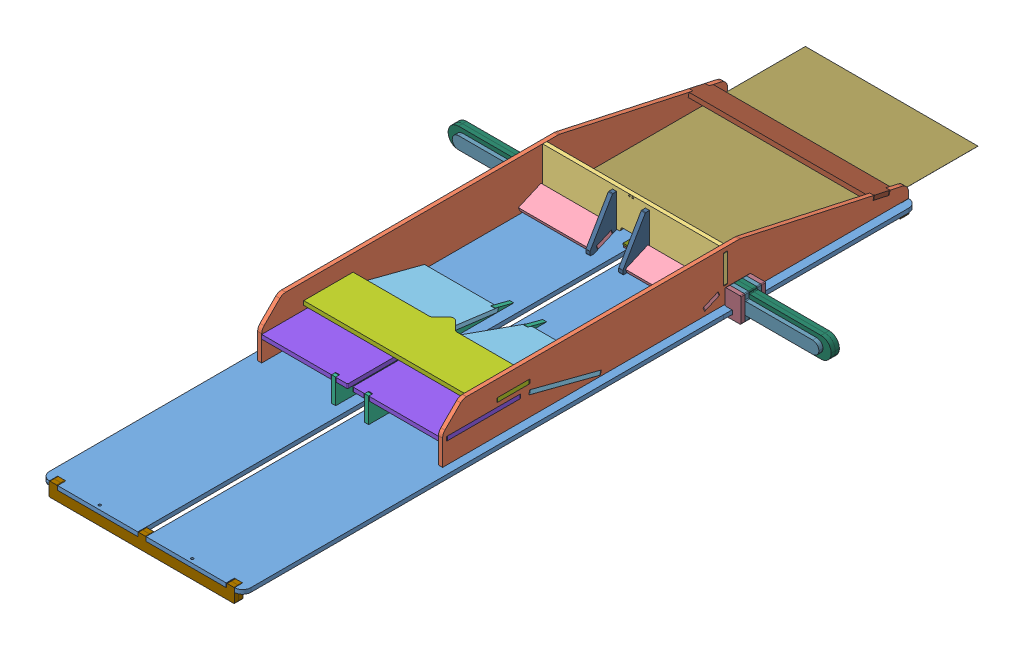
SolidWorks assembly assembly plane folder, configuration Default. Lengths in mm.
Overall size (466 77 820).
30 component instances, 16 part files, 6 mates.
Components (placement in the parent):
- frame-1: frame [Default] at (-2.7129 -3.6474 600) size (245.6 77 820)
  - backplate-1: backplate [Default] at (-118.702 1.298 900) size (245.6 5 820)
  - side-1: side [Default] at (-108.702 86.298 910) x (0 -1 0) z (1 0 0) size (64.9 566.78 5)
  - side-2: side [Default] at (111.298 86.298 910) x (0 -1 0) z (1 0 0) size (64.9 566.78 5)
  - frame-folder-1: frame-folder [Default] at (-103.702 21.248 530) size (225 45 5)
  - frame-folder2-1: frame-folder2 [Default] at (111.298 13.9006 564.4496) x (-1 0 0) z (0 -0.916515 -0.4) size (95 30 5)
  - frame-folder2-2: frame-folder2 [Default] at (-18.702 13.8606 564.5413) x (-1 0 0) z (0 -0.916515 -0.4) size (95 30 5)
  - frame-secondfold-1: frame-secondfold [Default] at (-103.702 31.4463 776.7345) x (1 0 0) z (0 0.967829 -0.251609) size (109.34 100 5)
  - frame-secondfold3-1: frame-secondfold3 [Default] at (-18.702 1.298 906.1881) x (0 0 -1) z (1 0 0) size (216.66 35.16 5)
  - frame-secondfold-3: frame-secondfold [Default] at (111.298 36.2855 775.3765) x (-1 0 0) z (0 -0.967829 0.251609) size (109.34 100 5)
  - frame-secondfold3-2: frame-secondfold3 [Default] at (21.298 1.298 906.0881) x (0 0 -1) z (1 0 0) size (216.66 35.16 5)
  - frame-secondfold1-1: frame-secondfold1 [Default] at (-103.702 41.4589 825.6357) x (1 0 0) z (0 1 0) size (225 72.93 5)
  - frame-secondfold4-1: frame-secondfold4 [Default] at (-103.702 31.4589 876.8329) x (1 0 0) z (0 1 0) size (109.5 100.05 5)
  - frame-secondfold4-2: frame-secondfold4 [Default] at (111.298 31.4589 776.6329) x (-1 0 0) z (0 1 0) size (109.5 100.05 5)
  - stopper-1: stopper [Default] at (-109.002 -10.702 1125) size (225.6 17 5)
  - stopper-2: stopper [Default] at (-109.002 -10.702 1120) size (225.6 17 5)
  - stopper-3: stopper [Default] at (-109.002 -10.702 315) size (225.6 17 5)
  - stopper-4: stopper [Default] at (-109.002 -10.702 310) size (225.6 17 5)
  - frame-folder4-1: frame-folder4 [Default] at (-18.702 61.198 535) x (0 -1 0) z (1 0 0) size (52 37.5 5)
  - frame-folder4-2: frame-folder4 [Default] at (21.298 61.198 535) x (0 -1 0) z (1 0 0) size (52 37.5 5)
  - frame-paperholder-1: frame-paperholder [Default] at (-108.702 25.1666 327.6234) x (1 0 0) z (0 -0.976744 0.214407) size (225 30 5)
- A4 paper-1: A4 paper [Default] at (-103.9148 7.9007 1115) x (1 0 0) z (0 1 0) size (210 297 0.1) (hidden)
- slider2-1: slider2 [Default] at (-49.729 -16.7544 842.5) size (466 32.7 30.31)
  - slider2-1-1: slider2-1 [Default] at (-81.7359 9.355 262.5) size (266 30 5)
  - slider2-2-1: slider2-2 [Default] at (-81.7359 9.355 267.5) size (446 30 5)
  - slider2-3-1: slider2-3 [Default] at (-81.7359 9.355 272.5) size (466 30 5)
  - slider2-3-2: slider2-3 [Default] at (-81.7359 9.355 277.5) size (466 30 5)
  - slider2-2-2: slider2-2 [Default] at (-81.7359 9.355 282.5) size (446 30 5)
  - slider2-1-2: slider2-1 [Default] at (-81.7359 9.355 287.5) size (266 30 5)
  - clip2-1: clip2 [Default] at (41.0141 21.655 292.5) x (1 0 0) z (0 1 0) size (20.89 30.31 20.4) (hidden)
Mates (geometry in assembly coordinates):
- Distance3: distance = 2.5 mm anti-aligned: plane of A4 paper-1 through (-103.9148 8.0007 1115) normal (-1 0 0); plane of frame-1/side-1 through (-106.4148 82.6507 1510) normal (1 0 0)
- Distance4: distance = 0.05 mm anti-aligned: plane of slider2-1/slider2-1-2 through (-121.4648 -2.3993 1135) normal (0 1 0); plane of frame-1/backplate-1 through (-121.4148 -2.3493 1500) normal (0 -1 0)
- Distance9: distance = 0.05 mm anti-aligned: plane of frame-1/backplate-1 through (-121.4148 2.6507 1500) normal (-1 0 0); plane of slider2-1/slider2-1-2 through (-121.4648 -2.3993 1135) normal (1 0 0)
- Coincident10: coincident: plane of A4 paper-1 through (-103.9148 8.0007 1115) normal (0 0 1); line of slider2-1/slider2-3-1 through (11.2852 4.9007 1115) axis (-1 0 0)
- LimitDistance2: limit distance = 195 mm aligned: plane of slider2-1/slider2-1-1 through (-131.4648 -7.3993 1105) normal (0 0 -1); plane of frame-1/backplate-1 through (-121.4148 2.6507 910) normal (0 0 -1)
- Distance8: distance = 1 mm anti-aligned: plane of A4 paper-1 through (-103.9148 7.9007 1115) normal (0 -1 0); plane of slider2-1/clip2-1 through (-8.7148 6.9007 1135) normal (0 1 0)
